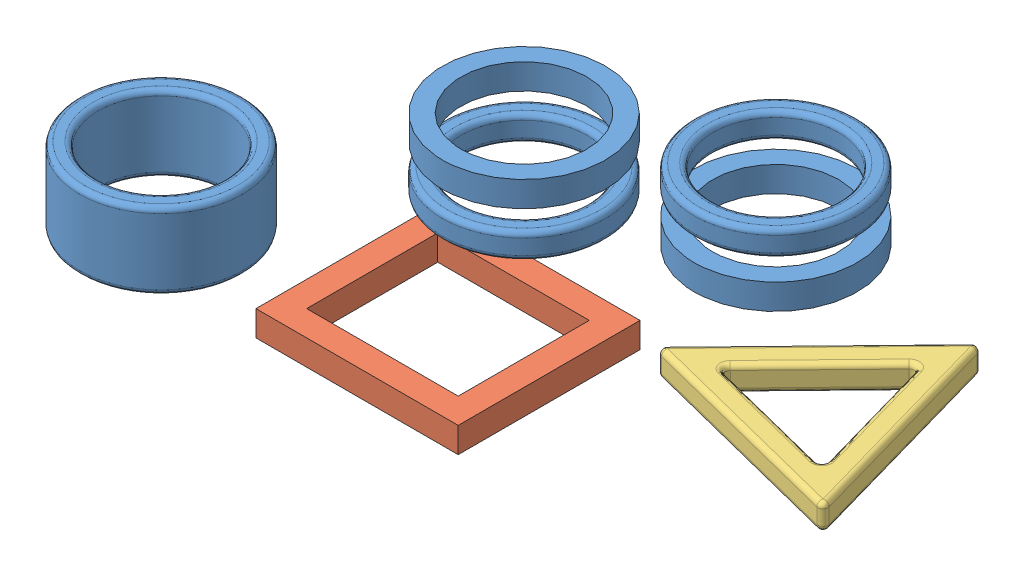
SolidWorks assembly top_level, configuration mainConfig1. Lengths in mm.
Overall size (251.38 56.44 168.53).
9 component instances, 3 part files, 0 mates.
Components (placement in the parent):
- two_circles-1: two_circles [two_circles_config1] at (11.2698 -16.6662 5.3758) size (65.59 27.98 65.59)
  - circle-1: circle [Circle_Config1] at (-14.1587 7.4697 2.3965) size (64.24 10 64.24)
  - circle-2: circle [Circle_Config2_nf] at (-14.1587 25.4501 2.3965) x (0.999776 0 -0.021142) z (0.021142 0 0.999776) size (64.24 10 64.24)
- two_circles-2: two_circles [two_circles_config2] at (76.735 -17.8572 -28.3601) size (65.59 27.98 65.59)
  - circle-1: circle [Circle_Config2_nf] at (-14.1587 7.4697 2.3965) size (64.24 10 64.24)
  - circle-2: circle [Circle_Config1] at (-14.1587 25.4501 2.3965) x (0.999776 0 -0.021142) z (0.021142 0 0.999776) size (64.24 10 64.24)
- circle-1: circle [Circle_config3_fat] at (-75.9907 -22.5033 77.6546) size (64.24 30 64.24)
- square-1: square [square_config2_nf] at (6.5579 -37.5668 44.2075) size (79.71 10 71.65)
- triangle-1: triangle [triangle_config1] at (106.2947 -37.6519 0.1211) size (85.9 10 85.27)
